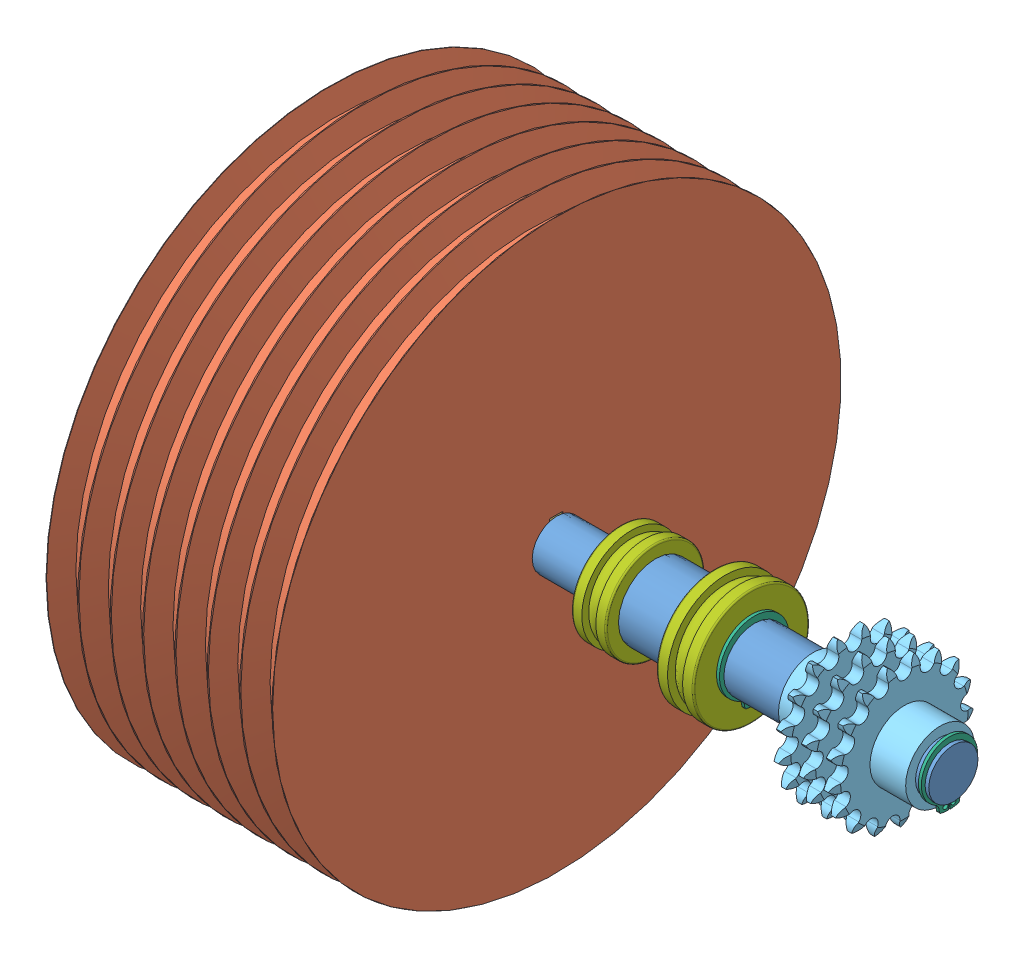
SolidWorks assembly Assem1, configuration Default. Lengths in mm.
Overall size (255.5 230.82 230.82).
11 component instances, 7 part files, 26 mates.
Components (placement in the parent):
- shaft 1-1: shaft 1 [Default] at (-28.398 17.3563 3.1936) size (255.5 30 30)
- pulley1-1: pulley1 [Default] at (-147.0756 124.0363 3.1936) size (92 230.82 230.82)
- khar pulley-1: khar pulley [Default] at (-61.648 25.3563 3.6936) x (0 0 1) z (-1 0 0) size (5 5 10)
- khar charkhzanjir -1: khar charkhzanjir  [Default] at (50.352 26.8563 3.1936) x (0 0 1) z (-1 0 0) size (6 6 8)
- sprocket1-1: sprocket1 [Default] at (77.102 17.3563 3.1936) x (-1 0 0) z (0 0 -1) size (51.62 58.55 58.8)
- circlip for shafts normal_din-1: circlip for shafts normal_din [Circlip DIN 471 - 17 x 1] at (-153.548 17.3563 3.1936) x (0 -0.547774 -0.836627) z (1 0 0) size (19.57 22.3 1)
- thrust ball bearing_68_skf-1: thrust ball bearing_68_skf [SKF - 51204 - 10,SI,NC,10_68] at (-28.648 17.3563 3.1936) x (1 0 0) z (0 -0.121367 0.992608) size (14 40 40)
- thrust ball bearing_68_skf-3: thrust ball bearing_68_skf [SKF - 51205 - 12,SI,NC,12_68] at (9.852 17.3563 3.1936) x (1 0 0) z (0 0.066371 0.997795) size (15 47 47)
- circlip for shafts normal_din-2: circlip for shafts normal_din [Circlip DIN 471 - 20 x 1.2] at (-35.748 17.3563 3.1936) x (0 -0.023614 -0.999721) z (1 0 0) size (22.81 25.6 1.2)
- circlip for shafts normal_din-3: circlip for shafts normal_din [Circlip DIN 471 - 25 x 1.2] at (18.552 17.3563 3.1936) x (0 0 -1) z (1 0 0) size (28.33 31.3 1.2)
- circlip for shafts normal_din-4: circlip for shafts normal_din [Circlip DIN 471 - 20 x 1.2] at (97.752 17.3563 3.1936) x (0 0 -1) z (1 0 0) size (22.81 25.6 1.2)
Mates (geometry in assembly coordinates):
- Concentric1: concentric anti-aligned: cylinder of shaft 1-1 through (-156.148 17.3563 3.1936) axis (-1 0 0) radius 8.5; cylinder of pulley1-1 through (-153.647 17.3563 3.1936) axis (1 0 0) radius 8.5
- Coincident2: coincident anti-aligned: plane of khar pulley-1 through (-71.648 25.3563 3.6936) normal (-1 0 0); circle of shaft 1-1
- Coincident3: coincident anti-aligned: plane of shaft 1-1 through (-71.648 22.8563 0.1936) normal (0 1 0); plane of khar pulley-1 through (-71.648 22.8563 1.1936) normal (0 -1 0)
- Coincident4: coincident anti-aligned: plane of shaft 1-1 through (-61.648 25.8563 3.1936) normal (-1 0 0); plane of khar pulley-1 through (-61.648 25.3563 3.6936) normal (1 0 0)
- Coincident5: coincident anti-aligned: plane of shaft 1-1 through (-61.648 25.8563 3.1936) normal (-1 0 0); plane of khar pulley-1 through (-61.648 25.3563 3.6936) normal (1 0 0)
- Coincident6: coincident anti-aligned: plane of shaft 1-1 through (-71.648 22.8563 6.1936) normal (0 0 -1); plane of khar pulley-1 through (-71.648 22.8563 6.1936) normal (0 0 1)
- Parallel1: parallel anti-aligned: plane of pulley1-1 through (-71.648 27.7803 5.6936) normal (0 -1 0); plane of khar pulley-1 through (-71.648 27.8563 1.1936) normal (0 1 0)
- Coincident8: coincident anti-aligned: circle of shaft 1-1; plane of pulley1-1 through (-61.648 17.3563 3.1936) normal (1 0 0)
- Coincident9: coincident anti-aligned: plane of shaft 1-1 through (42.352 29.8563 3.1936) normal (1 0 0); plane of khar charkhzanjir -1 through (42.352 26.8563 3.1936) normal (-1 0 0)
- Coincident10: coincident anti-aligned: plane of shaft 1-1 through (50.352 27.3563 6.1936) normal (0 0 -1); plane of khar charkhzanjir -1 through (42.352 23.8563 6.1936) normal (0 0 1)
- Coincident11: coincident anti-aligned: plane of shaft 1-1 through (50.352 23.8563 6.1936) normal (0 1 0); plane of khar charkhzanjir -1 through (42.352 23.8563 0.1936) normal (0 -1 0)
- Concentric3: concentric aligned: cylinder of shaft 1-1 through (-156.148 17.3563 3.1936) axis (-1 0 0) radius 10; cylinder of sprocket1-1 through (93.972 17.3563 3.1936) axis (-1 0 0) radius 10
- Parallel2: parallel anti-aligned: plane of khar charkhzanjir -1 through (42.352 29.8563 0.1936) normal (0 1 0); plane of sprocket1-1 through (50.352 29.6956 0.1936) normal (0 -1 0)
- Coincident19: coincident anti-aligned: plane of shaft 1-1 through (42.352 29.8563 3.1936) normal (1 0 0); plane of sprocket1-1 through (42.352 17.3563 3.1936) normal (-1 0 0)
- Concentric4: concentric anti-aligned: cylinder of shaft 1-1 through (-156.148 17.3563 3.1936) axis (-1 0 0) radius 8.1; cylinder of circlip for shafts normal_din-1 through (-154.548 17.3563 3.1936) axis (1 0 0) radius 8.1
- Coincident21: coincident anti-aligned: plane of shaft 1-1 through (-153.548 25.8563 3.1936) normal (-1 0 0); plane of circlip for shafts normal_din-1 through (-153.548 17.3563 3.1936) normal (1 0 0)
- Coincident22: coincident anti-aligned: plane of shaft 1-1 through (-21.648 27.3563 3.1936) normal (-1 0 0); plane of thrust ball bearing_68_skf-1 through (-21.648 27.8779 4.4801) normal (1 0 0)
- Concentric5: concentric aligned: cylinder of shaft 1-1 through (-156.148 17.3563 3.1936) axis (-1 0 0) radius 10; cylinder of thrust ball bearing_68_skf-1 through (6.277 17.3563 3.1936) axis (-1 0 0) radius 10
- Concentric6: concentric aligned: cylinder of shaft 1-1 through (-156.148 17.3563 3.1936) axis (-1 0 0) radius 12.5; cylinder of thrust ball bearing_68_skf-3 through (44.777 17.3563 3.1936) axis (-1 0 0) radius 12.5
- Coincident23: coincident anti-aligned: plane of shaft 1-1 through (2.352 32.3563 3.1936) normal (1 0 0); plane of thrust ball bearing_68_skf-3 through (2.352 30.4274 2.3242) normal (-1 0 0)
- Concentric8: concentric anti-aligned: cylinder of shaft 1-1 through (-156.148 17.3563 3.1936) axis (-1 0 0) radius 9.5; cylinder of circlip for shafts normal_din-2 through (-36.948 17.3563 3.1936) axis (1 0 0) radius 9.5
- Coincident24: coincident anti-aligned: plane of shaft 1-1 through (-36.948 27.3563 3.1936) normal (1 0 0); plane of circlip for shafts normal_din-2 through (-36.948 17.3563 3.1936) normal (-1 0 0)
- Concentric9: concentric anti-aligned: cylinder of shaft 1-1 through (-156.148 17.3563 3.1936) axis (-1 0 0) radius 11.95; cylinder of circlip for shafts normal_din-3 through (17.352 17.3563 3.1936) axis (1 0 0) radius 11.95
- Coincident25: coincident anti-aligned: plane of shaft 1-1 through (17.352 29.8563 3.1936) normal (1 0 0); plane of circlip for shafts normal_din-3 through (17.352 17.3563 3.1936) normal (-1 0 0)
- Concentric10: concentric: cylinder of shaft 1-1 through (-156.148 17.3563 3.1936) axis (-1 0 0) radius 9.5; cylinder of circlip for shafts normal_din-4 through (96.552 17.3563 3.1936) axis (1 0 0) radius 9.5
- Coincident26: coincident anti-aligned: plane of shaft 1-1 through (96.552 27.3563 3.1936) normal (1 0 0); plane of circlip for shafts normal_din-4 through (96.552 17.3563 3.1936) normal (-1 0 0)
